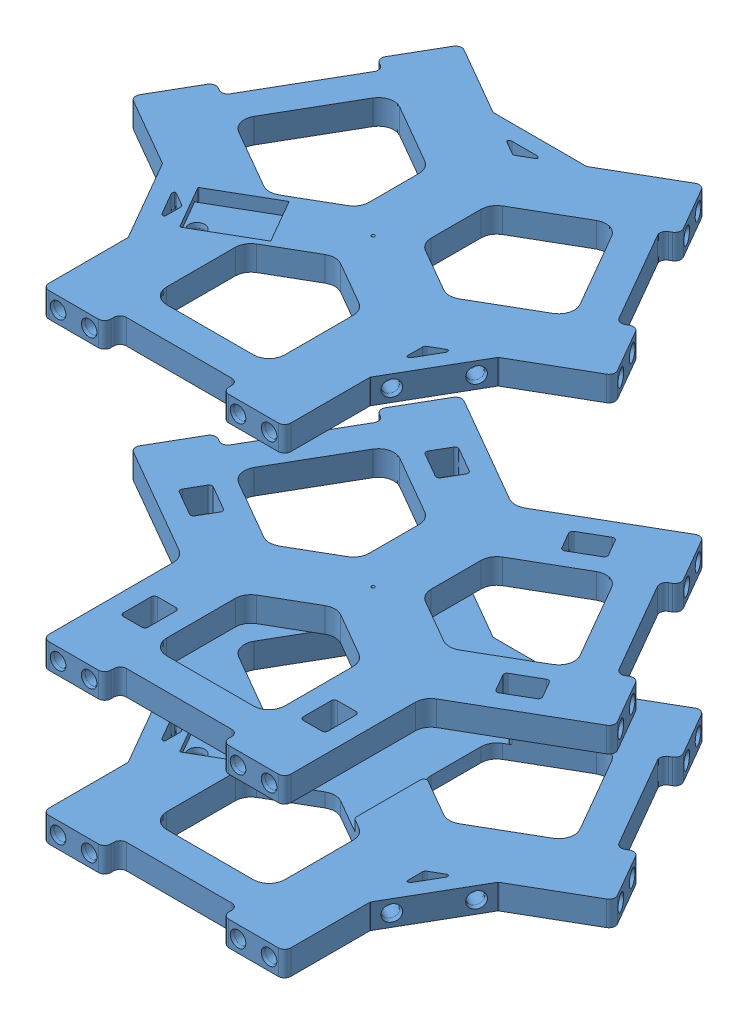
SolidWorks assembly stack, configuration Default. Lengths in mm.
Overall size (154.54 154.5 134.37).
3 component instances, 1 part files, 6 mates.
Components (placement in the parent):
- hex_base-1: hex_base [bottomTopPCA] at origin size (154.54 8 134.37)
- hex_base-2: hex_base [middle] at (0 48.5 0) size (154.54 8 134.37)
- hex_base-3: hex_base [bottomTop] at (0 146.5 0) size (154.54 8 134.37)
Mates (geometry in assembly coordinates):
- Coincident1: coincident aligned: plane of hex_base-1 through (-39 8 67.55) normal (0 0 1); plane of hex_base-2 through (-39 56.5 67.55) normal (0 0 1)
- Coincident2: coincident aligned: plane of hex_base-2 through (-39 56.5 67.55) normal (0 0 1); plane of hex_base-3 through (-39 154.5 67.55) normal (0 0 1)
- Coincident3: coincident aligned: plane of hex_base-1 through (78 8 0) normal (0.866025 0 -0.5); plane of hex_base-2 through (78 56.5 0) normal (0.866025 0 -0.5)
- Coincident4: coincident aligned: plane of hex_base-2 through (78 56.5 0) normal (0.866025 0 -0.5); plane of hex_base-3 through (78 154.5 0) normal (0.866025 0 -0.5)
- Distance1: distance = 40.5 mm anti-aligned: plane of hex_base-1 through (0 8 0) normal (0 1 0); plane of hex_base-2 through (0 48.5 0) normal (0 -1 0)
- Distance2: distance = 90 mm anti-aligned: plane of hex_base-2 through (0 56.5 0) normal (0 1 0); plane of hex_base-3 through (0 146.5 0) normal (0 -1 0)
